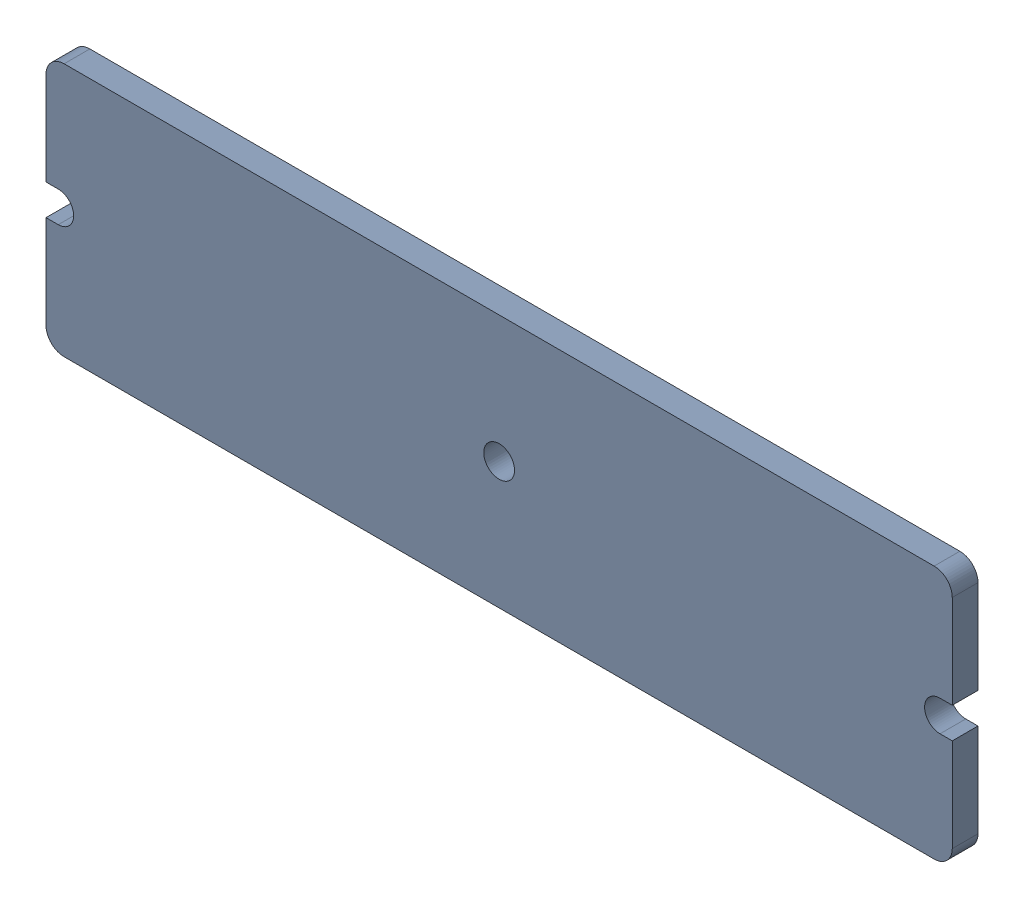
SolidWorks assembly PCB, configuration По умолчанию. Lengths in mm.
Overall size (100 28 2.84).
2 component instances, 1 part files, 0 mates.
Components (placement in the parent):
- Board-1: Board [По умолчанию] at origin size (100 28 2.84)
  - Board-Part-1-1: Board-Part-1 [По умолчанию] at (0 0 -2.8403) size (100 28 2.84)
